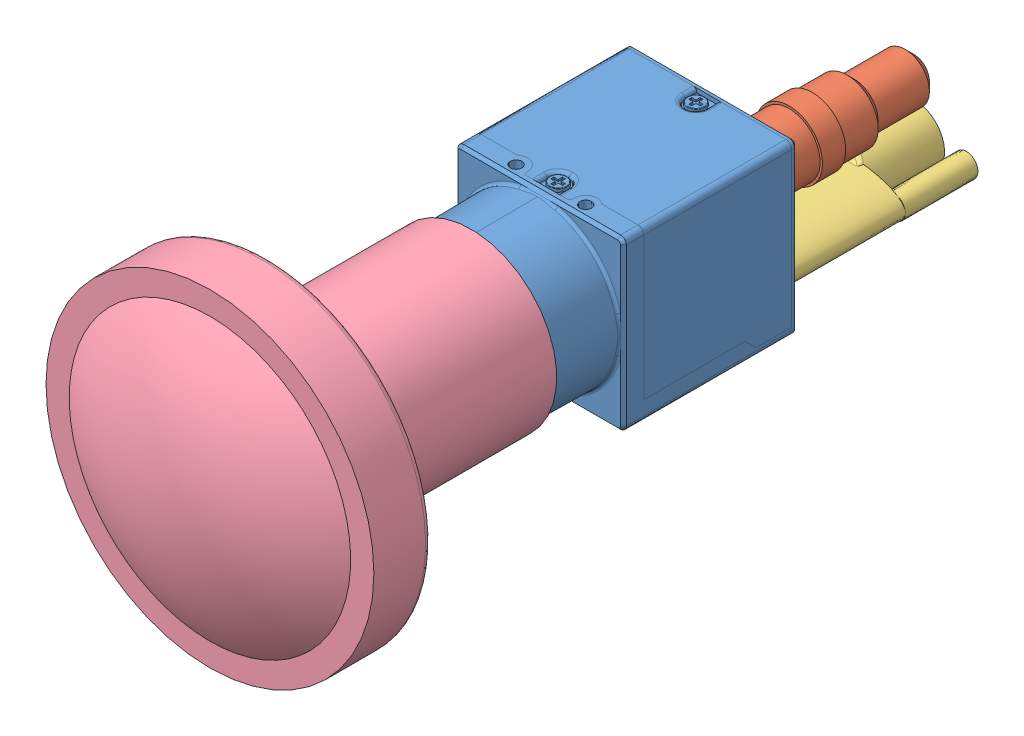
SolidWorks assembly BFS_U3_fisheye, configuration Default. Lengths in mm.
Overall size (73.83 73.83 128.56).
4 component instances, 4 part files, 11 mates.
Components (placement in the parent):
- FL2-020-R0-1: FL2-020-R0 [Default] at origin size (29 29 47.76)
- round_connector-1: round_connector [Default] at (7.25 7.25 -17.9182) x (0 0 -1) z (-0.517634 -0.855602 0) size (26.5 11.5 11.5)
- wide_connector-1: wide_connector [Default] at (0 -9.325 -18.2182) x (1 0 0) z (0 0 -1) size (22 10.5 33.5)
- FE185C086HA_1-2: FE185C086HA_1 [Default] at (0 0 16.3398) x (-0.923728 -0.383049 0) z (0 0 -1) size (56.5 56.5 60.5)
Mates (geometry in assembly coordinates):
- Coincident1: coincident anti-aligned: plane of FL2-020-R0_V2.step-1 through (-10 -7.325 -18.2182) normal (0 0 -1); plane of wide_connector-1 through (0 -9.325 -18.2182) normal (0 0 1)
- Concentric1: concentric anti-aligned: cylinder of FL2-020-R0_V2.step-1 through (-9 -9.325 -18.2182) axis (0 0 -1) radius 1; cylinder of wide_connector-1 through (-9 -9.325 -51.7182) axis (0 0 1) radius 2
- Concentric3: concentric anti-aligned: cylinder of FL2-020-R0_V2.step-1 through (9 -9.325 -18.2182) axis (0 0 -1) radius 1; cylinder of wide_connector-1 through (9 -9.325 -51.7182) axis (0 0 1) radius 2
- Concentric5: concentric aligned: circle of FL2-020-R0_V2.step-1; circle of round_connector-1
- Coincident3: coincident anti-aligned: plane of FL2-020-R0_V2.step-1 through (7.25 7.25 -17.9182) normal (0 0 -1); plane of round_connector-1 through (11.8275 4.4807 -17.9182) normal (0 0 1)
- Concentric6: concentric: cylinder of FL2-020-R0-1 through (0 0 22.9747) axis (0 0 1) radius 12.7; cylinder of FE185C086HA_1-1 through (0 0 28.9267) axis (0 0 -1) radius 11.2
- Coincident5: coincident anti-aligned: plane of FL2-020-R0-1 through (0 13.5741 24.6398) normal (0 0 1); plane of FE185C086HA_1-1 through (0 0 37.2267) normal (0 0 -1)
- Concentric7: concentric: cone of FL2-020-R0-1 through (0 0 13.132) axis (0 0 1); cylinder of Tamron_M111FM08_8mm-1 through (0 0 25.8359) axis (0 0 -1) radius 26.5
- Coincident6: coincident anti-aligned: plane of FL2-020-R0-1 through (0 13.5741 24.6398) normal (0 0 1); plane of Tamron_M111FM08_8mm-1 through (5.1846 25.9879 31.6359) normal (0 0 -1)
- Concentric8: concentric: cone of FL2-020-R0-1 through (0 0 13.132) axis (0 0 1); cylinder of FE185C086HA_1-2 through (0 0 85.1398) axis (0 0 -1) radius 11.2
- Coincident7: coincident anti-aligned: plane of FL2-020-R0-1 through (0 13.5741 24.6398) normal (0 0 1); plane of FE185C086HA_1-2 through (0 0 93.4398) normal (0 0 -1)
